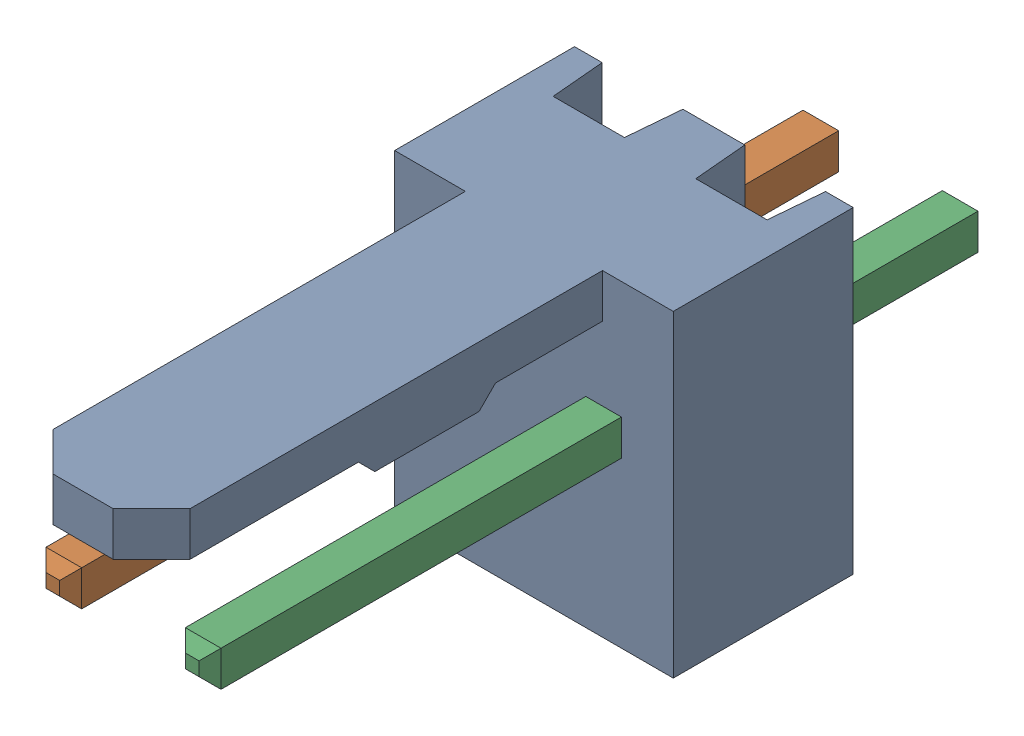
SolidWorks assembly Molex PCB 2 pin v2_7, configuration Default. Lengths in mm.
Overall size (5.08 5.79 14.92).
3 component instances, 2 part files, 0 mates.
Components (placement in the parent):
- BASE9710016_1-1: BASE9710016_1 [Default] at (2.54 2.895 -8.22) size (5.08 5.79 11.5)
- PINO9710016_1-1: PINO9710016_1 [Default] at (1.27 3.325 -0.72) size (0.65 0.65 14.2)
- PINO9710016_1-2: PINO9710016_1 [Default] at (3.81 3.325 -0.72) size (0.65 0.65 14.2)
